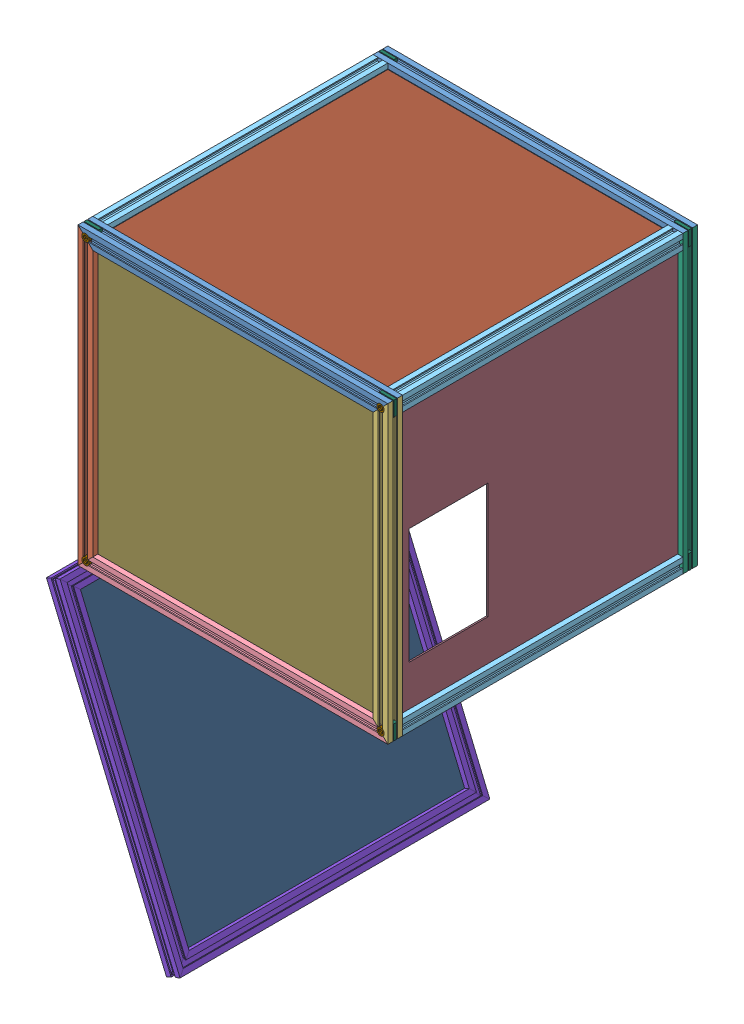
SolidWorks assembly BehaviorInnertbox, configuration 默认. Lengths in mm.
Overall size (462.93 822.94 420).
38 component instances, 15 part files, 0 mates.
Components (placement in the parent):
- Iner box-X3(JL-6-2020E) 420mm-1: Iner box-X3(JL-6-2020E) 420mm [默认] at (-136.4266 361.252 445) x (0 -1 0) z (1 0 0) size (20 20 420)
- Iner box-Y1(JL-6-2020E) 400mm-1: Iner box-Y1(JL-6-2020E) 400mm [默认] at (-136.4266 -38.748 425) x (0 0 1) z (0 1 0) size (20 20 400)
- Iner box-Y2(JL-6-2020E) 400mm-1: Iner box-Y2(JL-6-2020E) 400mm [默认] at (263.5734 -38.748 425) x (0 0 1) z (0 1 0) size (20 20 400)
- Iner box-X1(JL-6-2020E) 420mm-1: Iner box-X1(JL-6-2020E) 420mm [默认] at (-136.4266 -38.748 445) x (0 0 -1) z (1 0 0) size (20 20 420)
- Iner box-Z1(JL-6-2020E) 380mm-1: Iner box-Z1(JL-6-2020E) 380mm [默认] at (263.5734 361.252 425) x (1 0 0) z (0 0 -1) size (20 20 380)
- Iner box-Z1(JL-6-2020E) 380mm-2: Iner box-Z1(JL-6-2020E) 380mm [默认] at (263.5734 -18.748 425) x (1 0 0) z (0 0 -1) size (20 20 380)
- Iner box-Z1(JL-6-2020E) 380mm-3: Iner box-Z1(JL-6-2020E) 380mm [默认] at (-136.4266 -18.748 425) x (1 0 0) z (0 0 -1) size (20 20 380)
- Iner box-Z1(JL-6-2020E) 380mm-4: Iner box-Z1(JL-6-2020E) 380mm [默认] at (-116.4266 341.252 45) x (0 1 0) z (0 0 1) size (20 20 380)
- Iner box-X3(JL-6-2020E) 420mm-2: Iner box-X3(JL-6-2020E) 420mm [默认] at (283.5734 361.252 25) x (0 -1 0) z (-1 0 0) size (20 20 420)
- Iner box-Y1(JL-6-2020E) 400mm-2: Iner box-Y1(JL-6-2020E) 400mm [默认] at (-136.4266 361.252 45) x (0 0 -1) z (0 -1 0) size (20 20 400)
- Iner box-Y3(JL-6-2020E) 400mm-1: Iner box-Y3(JL-6-2020E) 400mm [默认] at (283.5734 -38.748 45) x (0 0 -1) z (0 1 0) size (20 20 400)
- Iner box-X2(JL-6-2020E) 420mm-1: Iner box-X2(JL-6-2020E) 420mm [默认] at (283.5734 -18.748 45) x (0 0 -1) z (-1 0 0) size (20 20 420)
- iner door(JL-6-2020E) 420mm-1: iner door(JL-6-2020E) 420mm [默认] at (-16.5741 -461.6851 25) x (0.921834 0.387585 0) z (0 0 1) size (20 20 420)
- iner door(JL-6-2020E) 420mm-2: iner door(JL-6-2020E) 420mm [默认] at (-179.3599 -74.5148 25) x (0.921834 0.387585 0) z (0.387585 -0.921834 0) size (20 20 420)
- iner door(JL-6-2020E) 420mm-3: iner door(JL-6-2020E) 420mm [默认] at (-16.5741 -461.6851 445) x (0.921834 0.387585 0) z (-0.387585 0.921834 0) size (20 20 420)
- iner door(JL-6-2020E) 420mm-4: iner door(JL-6-2020E) 420mm [默认] at (-179.3599 -74.5148 445) x (0.921834 0.387585 0) z (0 0 -1) size (20 20 420)
- M6-25mm-1: M6-25mm [默认] at (-126.4266 -28.748 439) size (10 10 31)
- M6-25mm-2: M6-25mm [默认] at (-126.4266 351.252 31) x (0.875472 0.483269 0) z (0 0 -1) size (10 10 31)
- M6-25mm-3: M6-25mm [默认] at (-126.4266 351.252 439) x (0.902761 0.430142 0) z (0 0 1) size (10 10 31)
- M6-25mm-4: M6-25mm [默认] at (273.5734 351.252 31) x (0.990077 0.140528 0) z (0 0 -1) size (10 10 31)
- M6-25mm-5: M6-25mm [默认] at (273.5734 351.252 439) size (10 10 31)
- M6-25mm-6: M6-25mm [默认] at (-126.4266 -28.748 31) x (-0.813233 0.581938 0) z (0 0 -1) size (10 10 31)
- _X2_94DD677F_X0_ Small-Door-1: _X2_94DD677F_X0_ Small-Door [默认] at (-12.7369 -442.1726 429.5) x (0 0 -1) z (0.921834 0.387585 0) size (388 388 2)
- _X2_94DD677F_X0_ Small-Back-1: _X2_94DD677F_X0_ Small-Back [默认] at (-119.9266 350.152 41.5) x (1 0 0) z (0 -1 0) size (388 388 2)
- _X2_94DD677F_X0_ Small-Bottom-1: _X2_94DD677F_X0_ Small-Bottom [默认] at (-119.9266 -23.248 438.1) x (0 1 0) z (0 0 -1) size (368 388 2)
- _X2_94DD677F_X0_ Small-Left-1: _X2_94DD677F_X0_ Small-Left [默认] at (276.6734 345.752 40.5) x (0 -1 0) z (-1 0 0) size (368 388 2)
- _X2_94DD677F_X0_ Small-Right-1: _X2_94DD677F_X0_ Small-Right [默认] at (-123.3266 -23.248 429.5) x (0 1 0) z (-1 0 0) size (368 388 2)
- _X2_94DD677F_X0_ Small-Bottom-2: _X2_94DD677F_X0_ Small-Bottom [默认] at (267.0734 345.752 33.9) x (0 -1 0) z (0 0 -1) size (368 388 2)
- M6-25mm-7: M6-25mm [默认] at (273.5734 -28.748 439) size (10 10 31)
- M6-25mm-8: M6-25mm [默认] at (273.5734 -28.748 31) x (0.590399 -0.807111 0) z (0 0 -1) size (10 10 31)
- 2020_X2_89D24EF6_X0_-1: 2020_X2_89D24EF6_X0_ [默认] at (-136.4266 356.252 31.9) size (20 20 6)
- 2020_X2_89D24EF6_X0_-2: 2020_X2_89D24EF6_X0_ [默认] at (283.5734 356.252 38.1) x (-1 0 0) z (0 0 -1) size (20 20 6)
- 2020_X2_89D24EF6_X0_-3: 2020_X2_89D24EF6_X0_ [默认] at (278.5734 -38.748 38.1) x (0 1 0) z (0 0 -1) size (20 20 6)
- 2020_X2_89D24EF6_X0_-4: 2020_X2_89D24EF6_X0_ [默认] at (278.5734 -38.748 438.1) x (0 1 0) z (0 0 -1) size (20 20 6)
- 2020_X2_89D24EF6_X0_-5: 2020_X2_89D24EF6_X0_ [默认] at (-136.4266 -33.748 38.1) x (1 0 0) z (0 0 -1) size (20 20 6)
- 2020_X2_89D24EF6_X0_-6: 2020_X2_89D24EF6_X0_ [默认] at (278.5734 361.252 431.9) x (0 -1 0) z (0 0 1) size (20 20 6)
- 2020_X2_89D24EF6_X0_-7: 2020_X2_89D24EF6_X0_ [默认] at (-136.4266 -33.748 438.1) x (1 0 0) z (0 0 -1) size (20 20 6)
- 2020_X2_89D24EF6_X0_-8: 2020_X2_89D24EF6_X0_ [默认] at (-136.4266 356.252 431.9) size (20 20 6)
